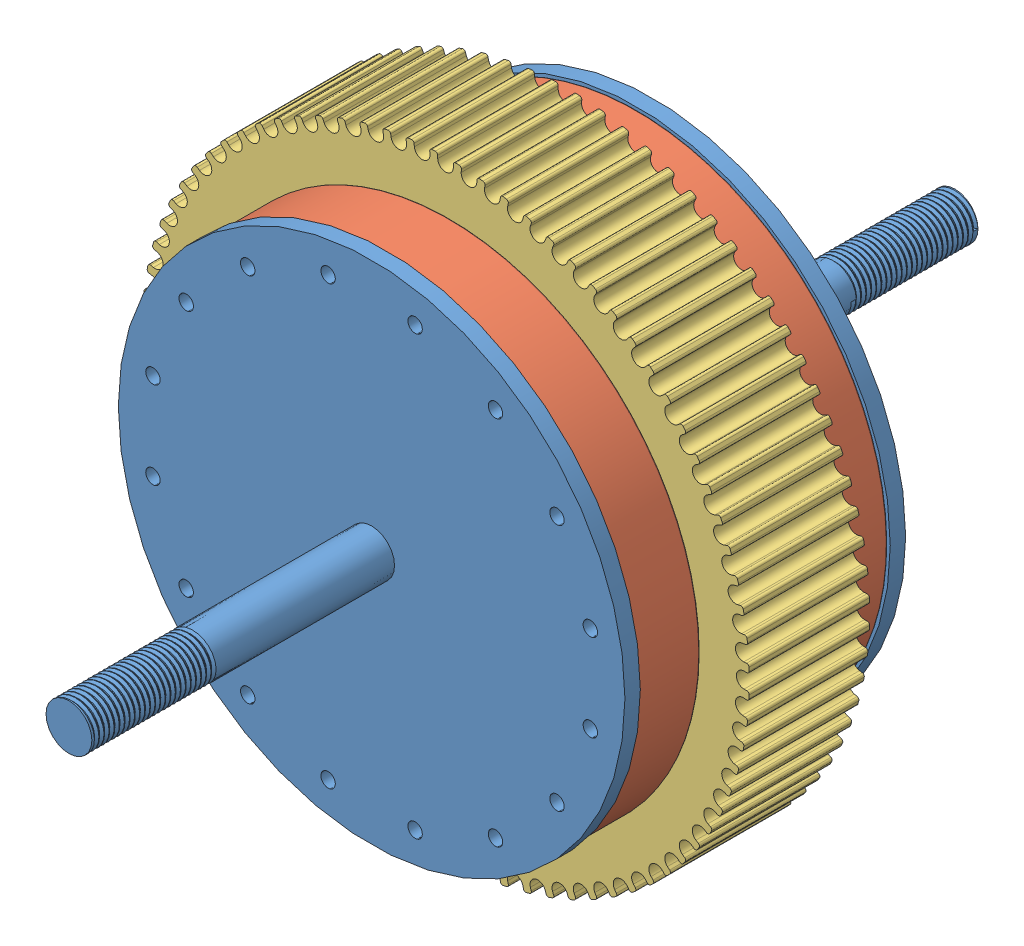
SolidWorks assembly Assem1, configuration Default. Lengths in mm.
Overall size (135.9 135.9 184).
4 component instances, 3 part files, 5 mates.
Components (placement in the parent):
- Gear-Hub-1: Gear-Hub [Default] at (-152.5466 137.8429 189.6136) size (105.2 105.2 184)
- Connecting-Bracket-1: Connecting-Bracket [Default] at (-152.5466 137.8429 209.3261) size (104 104 13.61)
- Final-Gear-Drive-80T-1: Final-Gear-Drive-80T [Default] at (-153.9103 136.8275 189.5482) size (126.11 126.11 25.11)
- Connecting-Bracket-2: Connecting-Bracket [Default] at (-152.5466 137.8429 170.3886) x (-0.923728 -0.383049 0) z (0 0 -1) size (104 104 13.61)
Mates (geometry in assembly coordinates):
- Lock1: lock: unknown of Gear-Hub-1; unknown of Connecting-Bracket-1
- Concentric3: concentric aligned: cone of Gear-Hub-1 through (-152.5466 137.8429 163.6636) axis (0 0 1); cylinder of Connecting-Bracket-2 through (-152.5466 137.8429 163.6636) axis (0 0 1) radius 44
- Coincident2: coincident anti-aligned: plane of Gear-Hub-1 through (-152.5466 137.8429 163.6636) normal (0 0 1); plane of Connecting-Bracket-2 through (-152.5466 137.8429 163.6636) normal (0 0 -1)
- Tangent5: tangent: cylinder of assembly; face of Gear-Hub-1; cylinder of Final-Gear-Drive-80T-1 through (-153.9103 136.8275 202.0482) axis (0 0 -1) radius 44
- Lock5: lock: unknown of Gear-Hub-1; unknown of Final-Gear-Drive-80T-1
